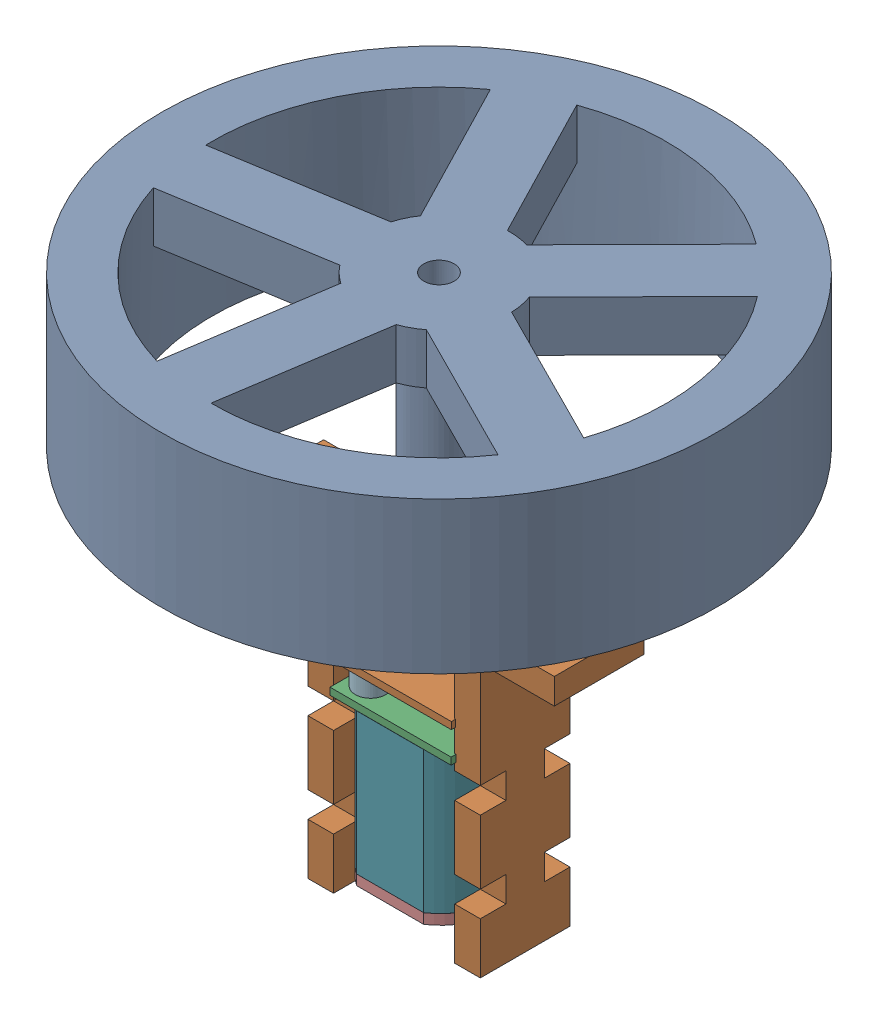
SolidWorks assembly Mobility System, configuration Default. Lengths in mm.
Overall size (63.16 54.05 63.16).
3 component instances, 3 part files, 4 mates.
Components (placement in the parent):
- MicroGearmotor v3-1: MicroGearmotor v3 [Default] at origin size (12.12 36.12 10.08)
- Wheel-1: Wheel [Default] at (5.9845 21.7491 -4.914) x (0 1 0) z (0.161542 0 0.986866) size (18 55 55)
- DriveMotorHolder-1: DriveMotorHolder [Default] at (23.4845 12.24 20.086) x (-1 0 0) z (0 -1 0) size (31.75 8.89 29.54)
Mates (geometry in assembly coordinates):
- Concentric1: concentric anti-aligned: circle of MicroGearmotor v3-1; circle of Wheel-1
- Concentric2: concentric anti-aligned: cylinder of MicroGearmotor v3-1 through (5.9845 9 -4.914) axis (0 1 0) radius 1.5; circle of DriveMotorHolder-1
- Coincident7: coincident anti-aligned: plane of MicroGearmotor v3-1 through (6 9.7 -5) normal (0 1 0); plane of DriveMotorHolder-1 through (23.4845 9.7 20.086) normal (0 -1 0)
- Parallel3: parallel aligned: plane of MicroGearmotor v3-1 through (9.4081 0 0.0334) normal (0 0 1); plane of DriveMotorHolder-1 through (21.8595 9.7 -0.469) normal (0 0 1)
